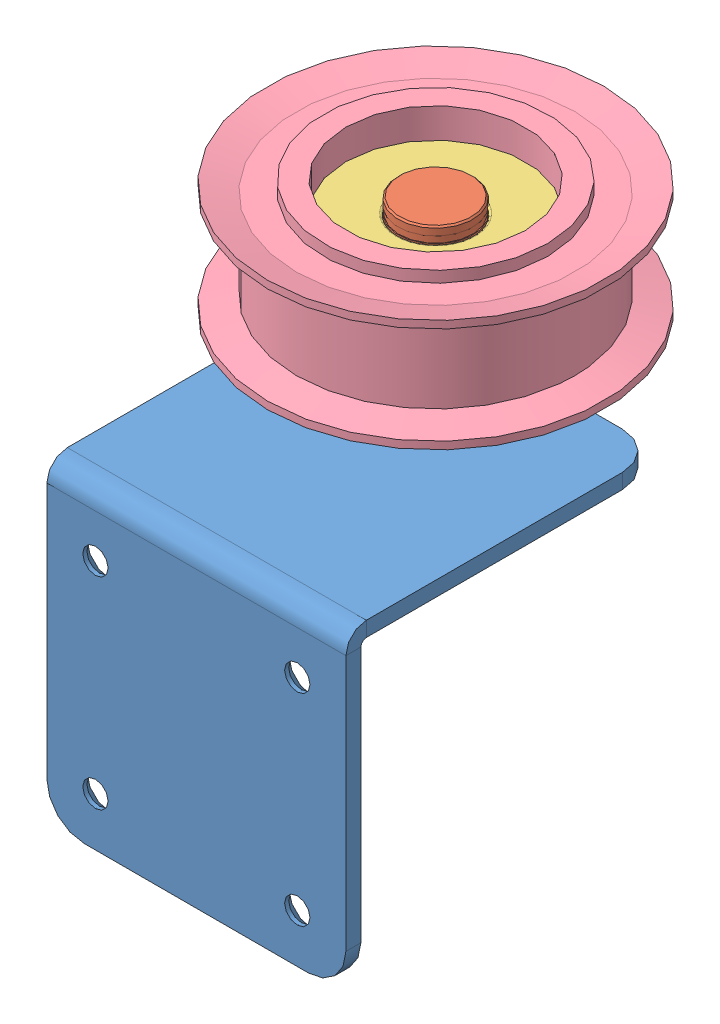
SolidWorks assembly 皮帶惰輪組-固定, configuration 預設. Lengths in mm.
Overall size (45 68.5 54.5).
5 component instances, 4 part files, 4 mates.
Components (placement in the parent):
- 皮帶惰輪座焊件-固定-1: 皮帶惰輪座焊件-固定 [預設] at (0 4 0) size (40 66.75 42)
  - 皮帶惰輪座-固定-1: 皮帶惰輪座-固定 [預設] at origin size (40 42 42)
  - 皮帶輪軸6-台面從動輪-1: 皮帶輪軸6-台面從動輪 [預設] at (20 0 10) x (-0.521747 0 -0.8531) z (0.8531 0 -0.521747) size (12 30.75 12)
- 軸承6000-1: 軸承6000 [預設] at (20 26.5 10) x (0 0 1) z (0 -1 0) size (26 26 8)
- 時規皮帶輪AHTF24S5M100-1: 時規皮帶輪AHTF24S5M100 [預設] at (20 22.5 10) x (0 0 1) z (1 0 0) size (45 16 45)
Mates (geometry in assembly coordinates):
- 同軸心5: concentric anti-aligned: cylinder of 皮帶惰輪座焊件-固定-1/皮帶輪軸6-台面從動輪-1 through (20 4 10) axis (0 -1 0) radius 5; cylinder of 軸承6000-1 through (20 18.5 10) axis (0 1 0) radius 5
- 重合/共線/共點66: coincident aligned: circle of 皮帶惰輪座焊件-固定-1/皮帶輪軸6-台面從動輪-1; plane of 軸承6000-1 through (20 18.5 10) normal (0 -1 0)
- 同軸心6: concentric anti-aligned: cylinder of 時規皮帶輪AHTF24S5M100-1 through (20 -26.84 10) axis (0 -1 0) radius 13; cylinder of 軸承6000-1 through (20 18.5 10) axis (0 1 0) radius 13
- 重合/共線/共點69: coincident anti-aligned: plane of 時規皮帶輪AHTF24S5M100-1 through (20 26.5 22) normal (0 -1 0); plane of 軸承6000-1 through (20 26.5 10) normal (0 1 0)
